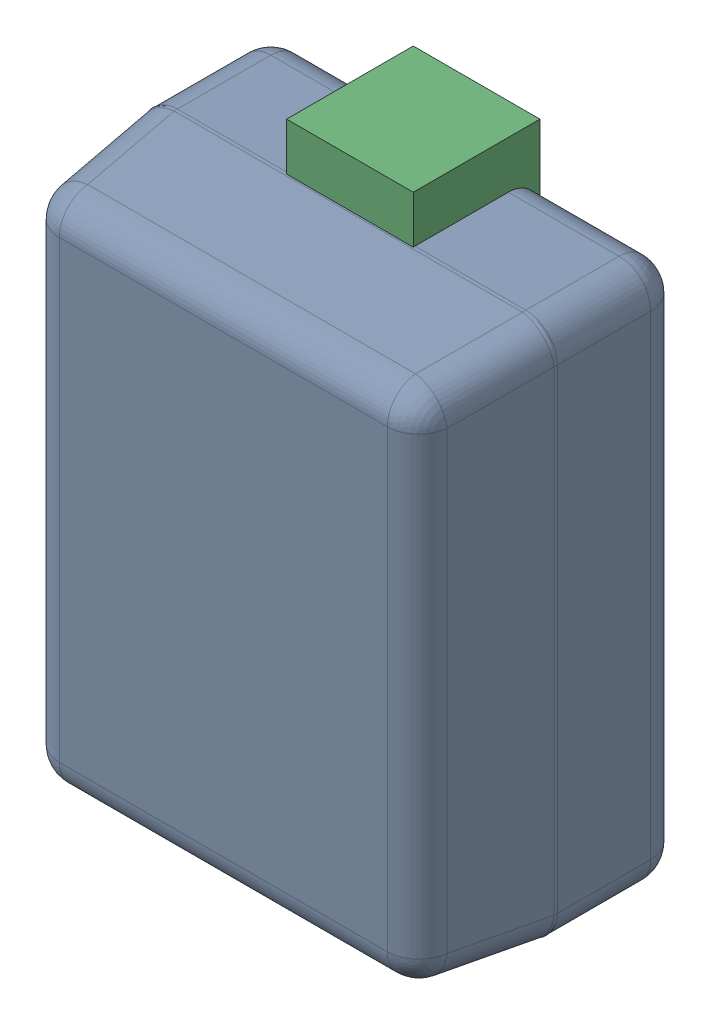
SolidWorks assembly D83.step, configuration Default. Lengths in mm.
Overall size (0.66 1 0.4).
5 component instances, 2 part files, 0 mates.
Components (placement in the parent):
- 6297722768.step-1: 6297722768.step [Default] at (24.6126 -1.9844 0) x (0 1 0) z (0 0 1) size (1 0.66 0.4)
  - Body (8).step-1: Body (8).step [Default] at (-0.425 -0.325 0) size (0.85 0.66 0.4)
    - Open CASCADE STEP translator 6.8 15.1.1.step-1: Open CASCADE STEP translator 6.8 15.1.1.step [Default] at origin size (0.85 0.66 0.4)
  - lead.step-1: lead.step [Default] at (-0.5 -0.1 0) size (0.19 0.2 0.2)
  - lead.step-2: lead.step [Default] at (0.5 0.1 0) x (-1 0 0) z (0 0 1) size (0.19 0.2 0.2)
